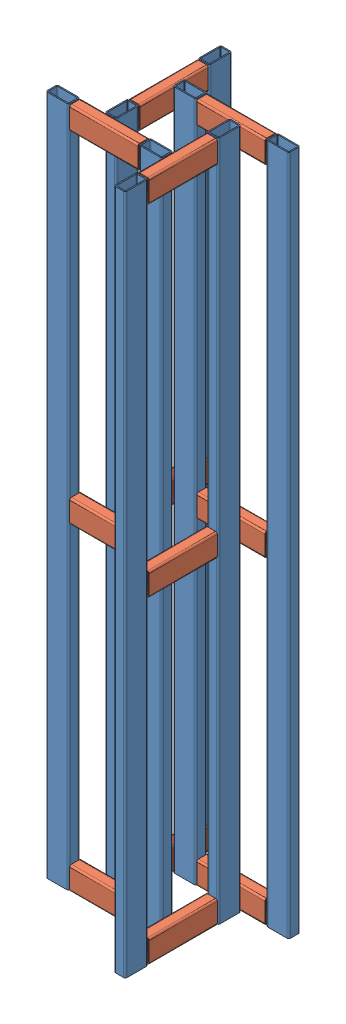
SolidWorks assembly Колонна15, configuration По умолчанию. Lengths in mm.
Overall size (308 1200 308).
24 component instances, 2 part files, 0 mates.
Components (placement in the parent):
- Щит1-1: Щит1 [По умолчанию] at origin size (204 1200 20)
  - Профиль2040-1: Профиль2040 [По умолчанию] at origin size (40 1200 20)
  - Профиль2040200-1: Профиль2040200 [По умолчанию] at (162 1160 0) x (0 1 0) z (0 0 1) size (40 120 20)
  - Профиль2040-2: Профиль2040 [По умолчанию] at (164 0 0) size (40 1200 20)
  - Профиль2040200-2: Профиль2040200 [По умолчанию] at (162 560 0) x (0 1 0) z (0 0 1) size (40 120 20)
  - Профиль2040200-3: Профиль2040200 [По умолчанию] at (162 0 0) x (0 1 0) z (0 0 1) size (40 120 20)
- Щит1-3: Щит1 [По умолчанию] at (100 0 0) x (0 0 1) z (-1 0 0) size (204 1200 20)
  - Профиль2040-1: Профиль2040 [По умолчанию] at origin size (40 1200 20)
  - Профиль2040200-1: Профиль2040200 [По умолчанию] at (162 1160 0) x (0 1 0) z (0 0 1) size (40 120 20)
  - Профиль2040-2: Профиль2040 [По умолчанию] at (164 0 0) size (40 1200 20)
  - Профиль2040200-2: Профиль2040200 [По умолчанию] at (162 560 0) x (0 1 0) z (0 0 1) size (40 120 20)
  - Профиль2040200-3: Профиль2040200 [По умолчанию] at (162 0 0) x (0 1 0) z (0 0 1) size (40 120 20)
- Щит1-4: Щит1 [По умолчанию] at (100 0 100) x (-1 0 0) z (0 0 -1) size (204 1200 20)
  - Профиль2040-1: Профиль2040 [По умолчанию] at origin size (40 1200 20)
  - Профиль2040200-1: Профиль2040200 [По умолчанию] at (162 1160 0) x (0 1 0) z (0 0 1) size (40 120 20)
  - Профиль2040-2: Профиль2040 [По умолчанию] at (164 0 0) size (40 1200 20)
  - Профиль2040200-2: Профиль2040200 [По умолчанию] at (162 560 0) x (0 1 0) z (0 0 1) size (40 120 20)
  - Профиль2040200-3: Профиль2040200 [По умолчанию] at (162 0 0) x (0 1 0) z (0 0 1) size (40 120 20)
- Щит1-5: Щит1 [По умолчанию] at (0 0 100) x (0 0 -1) z (1 0 0) size (204 1200 20)
  - Профиль2040-1: Профиль2040 [По умолчанию] at origin size (40 1200 20)
  - Профиль2040200-1: Профиль2040200 [По умолчанию] at (162 1160 0) x (0 1 0) z (0 0 1) size (40 120 20)
  - Профиль2040-2: Профиль2040 [По умолчанию] at (164 0 0) size (40 1200 20)
  - Профиль2040200-2: Профиль2040200 [По умолчанию] at (162 560 0) x (0 1 0) z (0 0 1) size (40 120 20)
  - Профиль2040200-3: Профиль2040200 [По умолчанию] at (162 0 0) x (0 1 0) z (0 0 1) size (40 120 20)
